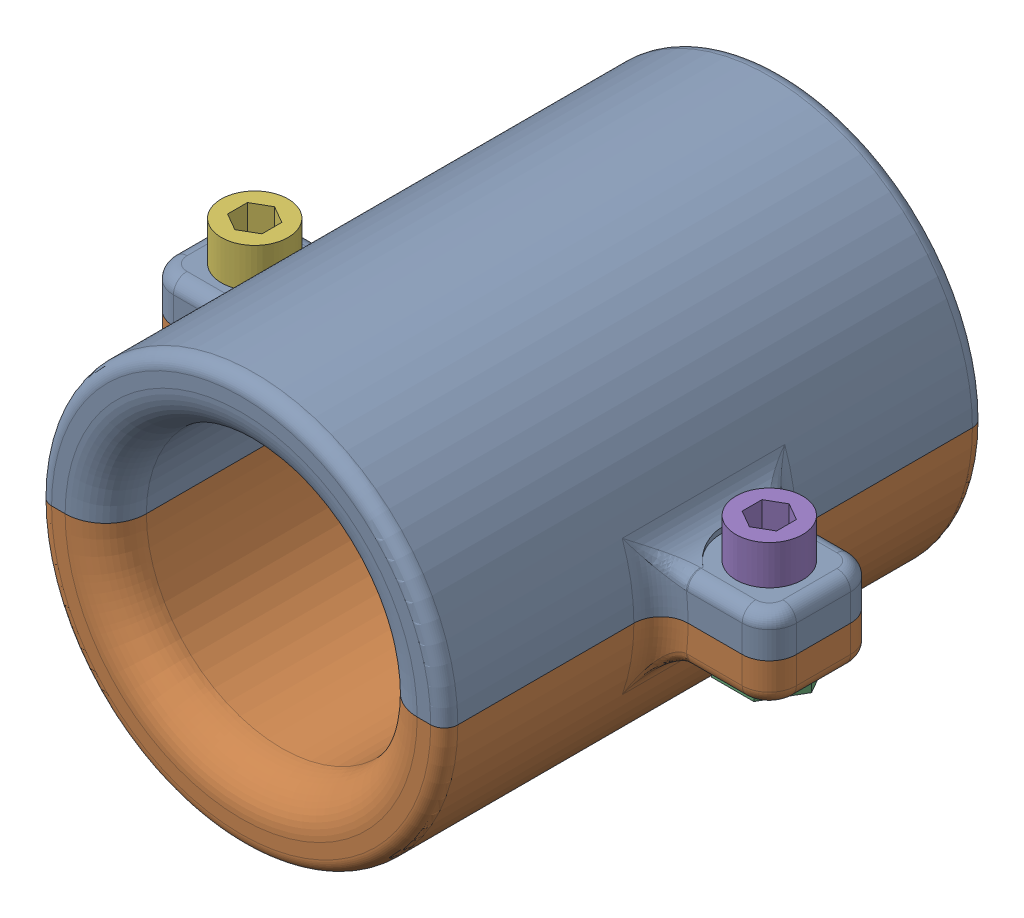
SolidWorks assembly Bar_Clamp, configuration Default. Lengths in mm.
Overall size (46 30 40).
6 component instances, 4 part files, 16 mates.
Components (placement in the parent):
- Test_Stand_Stopper_Screw_Part-1: Test_Stand_Stopper_Screw_Part [Default] at origin size (46 15 40)
- Test_Stand_Stopper_Nut_Part-1: Test_Stand_Stopper_Nut_Part [Default] x (-1 0 0) z (0 0 1) size (46 15 40)
- M3_Nut-1: M3_Nut [Default] at (19 -3.88 20) x (-0.5 0 -0.866025) z (0 1 0) size (6.25 5.41 2.38)
- M3_Nut-3: M3_Nut [Default] at (-19 -3.88 20) x (-0.5 0 -0.866025) z (0 1 0) size (6.25 5.41 2.38)
- M3_8-2: M3_8 [Default] at (19 5.9 20) x (-0.866025 0 0.5) z (0.5 0 0.866025) size (4.93 10.9 4.93)
- M3_8-3: M3_8 [Default] at (-19 5.9 20) x (0.866025 0 -0.5) z (-0.5 0 -0.866025) size (4.93 10.9 4.93)
Mates (geometry in assembly coordinates):
- Coincident1: coincident anti-aligned: plane of Test_Stand_Stopper_Screw_Part-1 through (0 0 40) normal (0 -1 0); plane of Test_Stand_Stopper_Nut_Part-1 through (0 0 40) normal (0 1 0)
- Concentric2: concentric anti-aligned: cylinder of Test_Stand_Stopper_Screw_Part-1 through (-19 3 20) axis (0 -1 0) radius 1.5; cylinder of Test_Stand_Stopper_Nut_Part-1 through (-19 -3 20) axis (0 1 0) radius 1.5
- Concentric3: concentric: cylinder of Test_Stand_Stopper_Nut_Part-1 through (19 -3 20) axis (0 1 0) radius 1.5; cylinder of M3_Nut-1 through (19 -1.5 20) axis (0 -1 0) radius 1.5
- Concentric5: concentric: cylinder of Test_Stand_Stopper_Nut_Part-1 through (-19 -3 20) axis (0 1 0) radius 1.5; cylinder of M3_Nut-3 through (-19 -1.5 20) axis (0 -1 0) radius 1.5
- Concentric7: concentric anti-aligned: cylinder of M3_8-1 through (19 -5 4) axis (0 1 0) radius 1.45; cylinder of M3_Nut-2 through (19 -1.5 4) axis (0 -1 0) radius 1.5
- Concentric8: concentric anti-aligned: cylinder of Test_Stand_Stopper_Screw_Part-1 through (19 3 20) axis (0 -1 0) radius 1.5; cylinder of M3_8-2 through (19 -5 20) axis (0 1 0) radius 1.45
- Coincident7: coincident anti-aligned: plane of Test_Stand_Stopper_Screw_Part-1 through (0 3 0) normal (0 1 0); plane of M3_8-2 through (19 3 20) normal (0 -1 0)
- Parallel6: parallel anti-aligned: plane of Test_Stand_Stopper_Screw_Part-1 through (23 3 24) normal (1 0 0); plane of M3_8-2 through (20.27 4 20.7332) normal (-1 0 0)
- Concentric9: concentric anti-aligned: cylinder of Test_Stand_Stopper_Screw_Part-1 through (-19 3 20) axis (0 -1 0) radius 1.5; cylinder of M3_8-3 through (-19 -5 20) axis (0 1 0) radius 1.45
- Coincident8: coincident anti-aligned: plane of Test_Stand_Stopper_Screw_Part-1 through (0 3 0) normal (0 1 0); plane of M3_8-3 through (-19 3 20) normal (0 -1 0)
- Parallel7: parallel anti-aligned: plane of Test_Stand_Stopper_Screw_Part-1 through (-23 3 24) normal (-1 0 0); plane of M3_8-3 through (-20.27 4 19.2668) normal (1 0 0)
- Coincident9: coincident aligned: circle of Test_Stand_Stopper_Screw_Part-1; cylinder of Test_Stand_Stopper_Nut_Part-1 through (19 -3 20) axis (0 1 0) radius 1.5
- Coincident10: coincident: plane of Test_Stand_Stopper_Nut_Part-1 through (0 -1.5 0) normal (0 -1 0); plane of M3_Nut-1 through (19 -1.5 20) normal (0 1 0)
- Parallel8: parallel aligned: plane of Test_Stand_Stopper_Nut_Part-1 through (17.4267 -1.5 22.725) normal (0.866025 0 -0.5); plane of M3_Nut-1 through (22.1235 -1.5 20) normal (0.866025 0 -0.5)
- Coincident11: coincident: plane of Test_Stand_Stopper_Nut_Part-1 through (0 -1.5 0) normal (0 -1 0); plane of M3_Nut-3 through (-19 -1.5 20) normal (0 1 0)
- Parallel9: parallel aligned: plane of Test_Stand_Stopper_Nut_Part-1 through (-20.5733 -1.5 22.725) normal (0 0 -1); plane of M3_Nut-3 through (-17.4383 -1.5 17.295) normal (0 0 -1)
